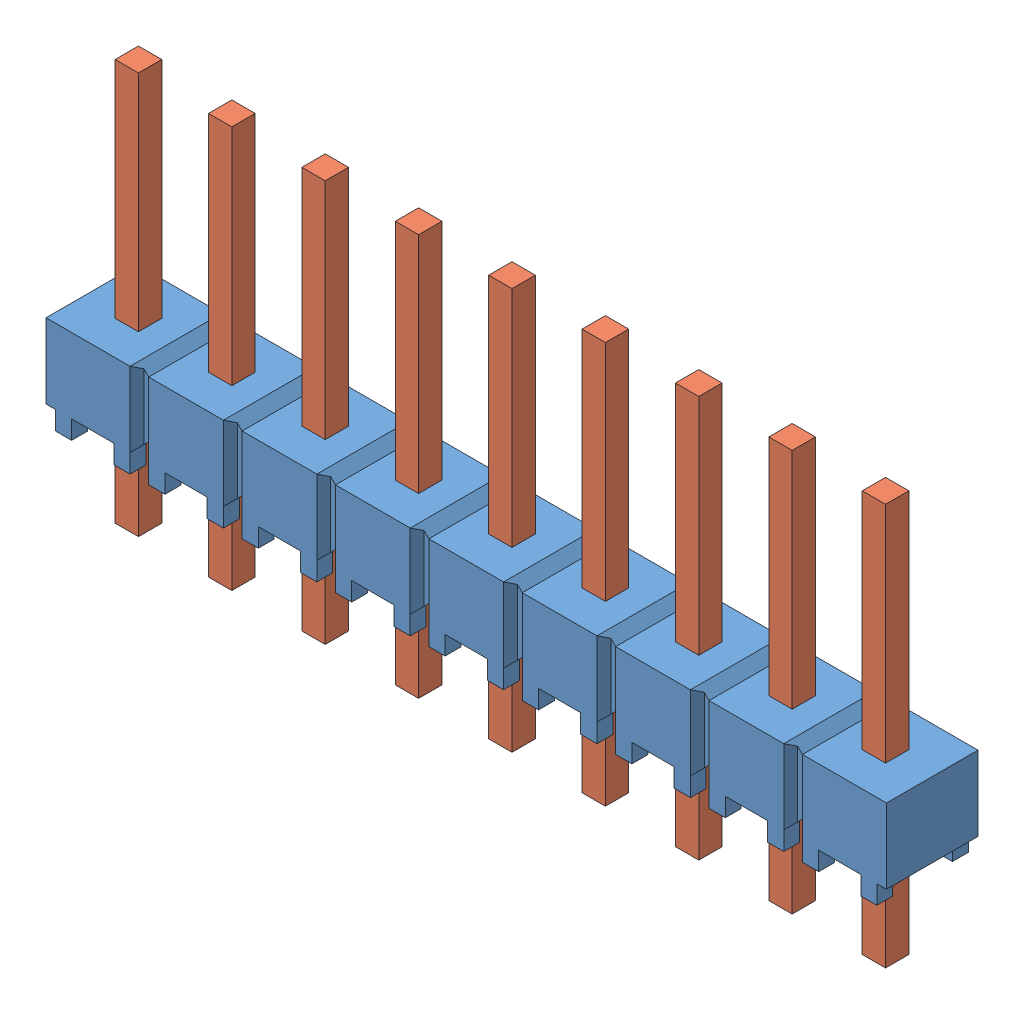
SolidWorks assembly HMTSW_109_07_G_S_240, configuration Default. Lengths in mm.
Overall size (22.86 10.92 2.49).
2 component instances, 2 part files, 0 mates.
Components (placement in the parent):
- _HMTSW_109_07_G_S_240_body_2-1: _HMTSW_109_07_G_S_240_body_2 [Default] at origin size (22.86 2.54 2.49)
- _HMTSW_109_07_S_240_4-1: _HMTSW_109_07_S_240_4 [Default] at (0 -2.286 0) size (21.21 10.92 0.89)
